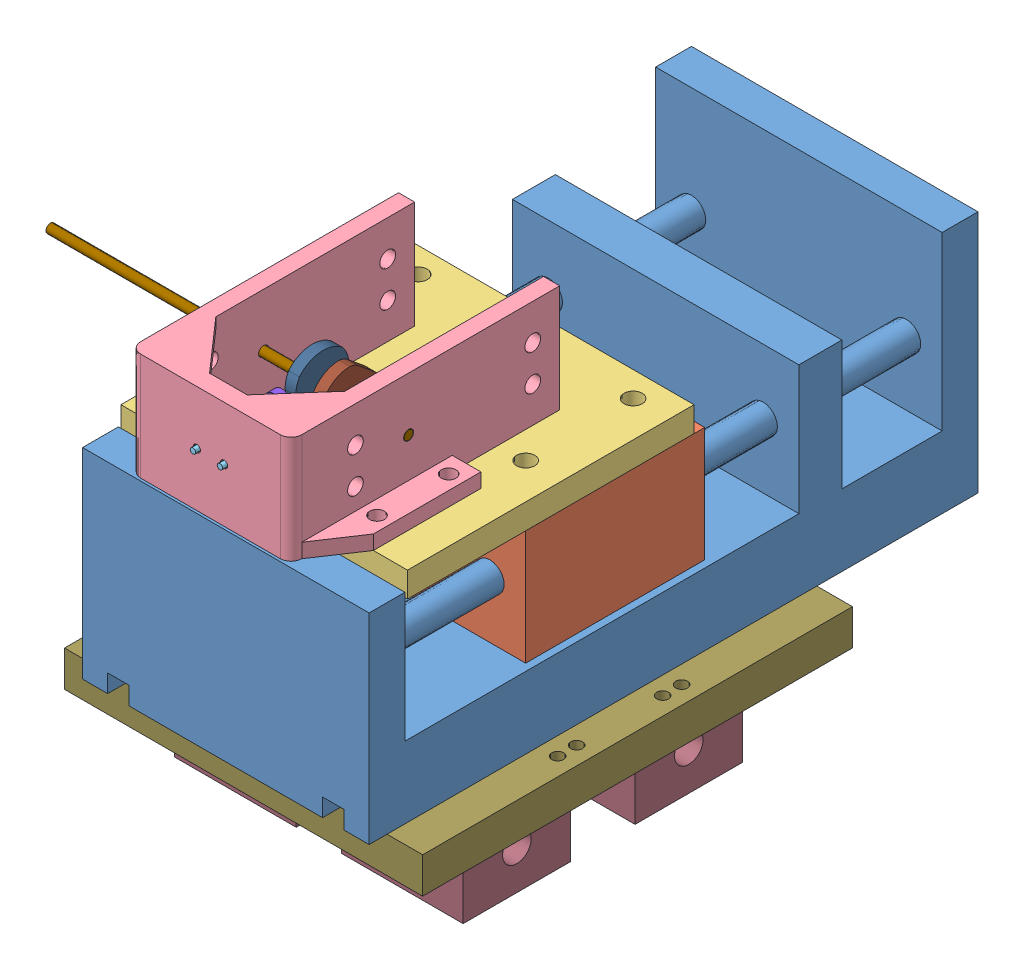
SolidWorks assembly Assembly of X Z and printhead, configuration Default. Lengths in mm.
Overall size (127.45 123 175.45).
21 component instances, 13 part files, 22 mates.
Components (placement in the parent):
- Main frame of smooth rod and bearing-1: Main frame of smooth rod and bearing [Default] at (46.0285 60.2399 135.9327) size (80 68 170)
- Bearing block of the z axis-1: Bearing block of the z axis [Default] at (46.0285 82.2399 152.2234) size (80 32 50)
- Print Head to Z adapter-2: Print Head to Z adapter [Default] at (46.0285 114.2399 152.2234) x (-1 0 0) z (0 0 -1) size (80 7 80)
- Print Head Assembly-2: Print Head Assembly [Default] at (55.1617 176.7471 226.2617) x (-1 0 0) z (0 -1 0) size (108 76.16 30)
  - Print Head Outershell-1: Print Head Outershell [Default] at (9.1332 1.0382 40.5072) size (61 75 30)
  - Printer Head Pins-1: Printer Head Pins [Default] at (5.3332 -0.1252 40.5072) size (1.5 13 1.5)
  - Printer Head Pins-3: Printer Head Pins [Default] at (12.9332 -0.0637 40.5072) size (1.5 13 1.5)
  - Print Head Adapter-1: Print Head Adapter [Default] at (5.3332 17.3748 40.5072) x (-0.971281 0 -0.237936) z (-0.237936 0 0.971281) size (7 9.5 7)
  - Print Head Adapter-2: Print Head Adapter [Default] at (12.9332 17.4363 40.5072) x (0.948692 0 0.316203) z (0.316203 0 -0.948692) size (7 9.5 7)
  - Brass Standoff in Print Head-1: Brass Standoff in Print Head [Default] at (12.9332 14.4363 40.5072) x (0.866025 0 0.5) z (-0.5 0 0.866025) size (5.5 6 4.76)
  - Brass Standoff in Print Head-2: Brass Standoff in Print Head [Default] at (5.3332 14.3748 40.5072) x (0.866025 0 0.5) z (-0.5 0 0.866025) size (5.5 6 4.76)
  - Screw In Printhead-1: Screw In Printhead [Default] at (12.9332 16.4363 40.5072) x (0.999742 0 0.022726) z (-0.022726 0 0.999742) size (5.2 8.33 5.2)
  - Screw In Printhead-2: Screw In Printhead [Default] at (5.3332 16.3748 40.5072) x (0.961094 0 -0.276221) z (0.276221 0 0.961094) size (5.2 8.33 5.2)
  - Axle-1: Axle [Default] at (-13.3668 33.8682 40.5072) size (100 2.5 2.5)
  - Gear 1 Print Head-1: Gear 1 Print Head [Default] at (13.5517 33.8682 40.5072) x (0 0.635335 -0.772236) z (0 0.772236 0.635335) size (17 3 17)
  - Gear 2 Print Head-1: Gear 2 Print Head [Default] at (5.9517 33.8682 40.5072) x (0 0.99532 -0.096634) z (0 0.096634 0.99532) size (16.95 3 16.9)
- Linear Bearings to Z axis-3: Linear Bearings to Z axis [Default] at (45.9785 60.2399 155.9327) x (1 0 0) z (0 0 -1) size (100 10 120)
- Lienar Bearing Blocks-2: Lienar Bearing Blocks [Default] at (69.2785 28.2399 131.9327) size (34 22 30)
- Lienar Bearing Blocks-3: Lienar Bearing Blocks [Default] at (22.6785 28.2399 131.9327) size (34 22 30)
- Lienar Bearing Blocks-4: Lienar Bearing Blocks [Default] at (69.2785 28.2399 179.9327) size (34 22 30)
- Lienar Bearing Blocks-5: Lienar Bearing Blocks [Default] at (22.6785 28.2399 179.9327) size (34 22 30)
Mates (geometry in assembly coordinates):
- Concentric1: concentric anti-aligned: cylinder of Main frame of smooth rod and bearing-1 through (16.0285 98.2399 60.9327) axis (0 0 1) radius 4; cylinder of Bearing block of the z axis-1 through (16.0285 98.2399 192.2234) axis (0 0 -1) radius 4
- Concentric2: concentric anti-aligned: cylinder of Main frame of smooth rod and bearing-1 through (76.0285 98.2399 60.9327) axis (0 0 1) radius 4; cylinder of Bearing block of the z axis-1 through (76.0285 98.2399 192.2234) axis (0 0 -1) radius 4
- Concentric5: concentric anti-aligned: cylinder of Bearing block of the z axis-1 through (16.0285 109.2399 137.2234) axis (0 1 0) radius 2.6; cylinder of Print Head to Z adapter-2 through (16.0285 121.2399 137.2234) axis (0 -1 0) radius 2.55
- Coincident7: coincident anti-aligned: plane of Bearing block of the z axis-1 through (46.0285 114.2399 152.2234) normal (0 1 0); plane of Print Head to Z adapter-2 through (46.0285 114.2399 152.2234) normal (0 -1 0)
- Coincident8: coincident anti-aligned: circle of Print Head to Z adapter-2; circle of Print Head Assembly-2/Print Head Outershell-1
- Coincident9: coincident anti-aligned: circle of Print Head to Z adapter-2; circle of Print Head Assembly-2/Print Head Outershell-1
- Concentric7: concentric anti-aligned: cylinder of Bearing block of the z axis-1 through (76.0285 109.2399 167.2234) axis (0 1 0) radius 2.6; cylinder of Print Head to Z adapter-2 through (76.0285 121.2399 167.2234) axis (0 -1 0) radius 2.55
- Distance2: distance = 45 mm aligned: plane of Main frame of smooth rod and bearing-1 through (46.0285 128.2399 50.9327) normal (0 0 -1); plane of Linear Bearings to Z axis-3 through (-4.0215 50.2399 95.9327) normal (0 0 -1)
- Tangent5: tangent anti-aligned: plane of Main frame of smooth rod and bearing-1 through (19.0285 65.2399 220.9327) normal (-1 0 0); cylinder of Linear Bearings to Z axis-3 through (15.9785 50.2399 110.9327) axis (0 1 0) radius 3.05
- Coincident16: coincident anti-aligned: plane of Main frame of smooth rod and bearing-1 through (46.0285 60.2399 135.9327) normal (0 -1 0); plane of Linear Bearings to Z axis-3 through (45.9785 60.2399 155.9327) normal (0 1 0)
- Concentric10: concentric anti-aligned: circle of Linear Bearings to Z axis-3; circle of Lienar Bearing Blocks-2
- Parallel2: parallel aligned: plane of Linear Bearings to Z axis-3 through (-4.0215 50.2399 95.9327) normal (0 0 -1); plane of Lienar Bearing Blocks-2 through (52.2785 50.2399 116.9327) normal (0 0 -1)
- Coincident20: coincident anti-aligned: plane of Linear Bearings to Z axis-3 through (45.9785 50.2399 155.9327) normal (0 -1 0); plane of Lienar Bearing Blocks-2 through (69.2785 50.2399 131.9327) normal (0 1 0)
- Concentric12: concentric anti-aligned: circle of Linear Bearings to Z axis-3; circle of Lienar Bearing Blocks-3
- Concentric13: concentric anti-aligned: circle of Linear Bearings to Z axis-3; circle of Lienar Bearing Blocks-3
- Coincident21: coincident anti-aligned: plane of Linear Bearings to Z axis-3 through (45.9785 50.2399 155.9327) normal (0 -1 0); plane of Lienar Bearing Blocks-3 through (22.6785 50.2399 131.9327) normal (0 1 0)
- Concentric14: concentric anti-aligned: cylinder of Linear Bearings to Z axis-3 through (78.2785 50.2399 167.9327) axis (0 1 0) radius 2; cylinder of Lienar Bearing Blocks-4 through (78.2785 50.2399 167.9327) axis (0 -1 0) radius 1.7
- Concentric15: concentric anti-aligned: cylinder of Linear Bearings to Z axis-3 through (60.2785 50.2399 191.9327) axis (0 1 0) radius 2; cylinder of Lienar Bearing Blocks-4 through (60.2785 50.2399 191.9327) axis (0 -1 0) radius 1.7
- Coincident24: coincident anti-aligned: plane of Linear Bearings to Z axis-3 through (45.9785 50.2399 155.9327) normal (0 -1 0); plane of Lienar Bearing Blocks-4 through (69.2785 50.2399 179.9327) normal (0 1 0)
- Concentric16: concentric anti-aligned: circle of Linear Bearings to Z axis-3; circle of Lienar Bearing Blocks-5
- Concentric17: concentric anti-aligned: circle of Linear Bearings to Z axis-3; circle of Lienar Bearing Blocks-5
- Coincident27: coincident anti-aligned: plane of Linear Bearings to Z axis-3 through (45.9785 50.2399 155.9327) normal (0 -1 0); plane of Lienar Bearing Blocks-5 through (22.6785 50.2399 179.9327) normal (0 1 0)
